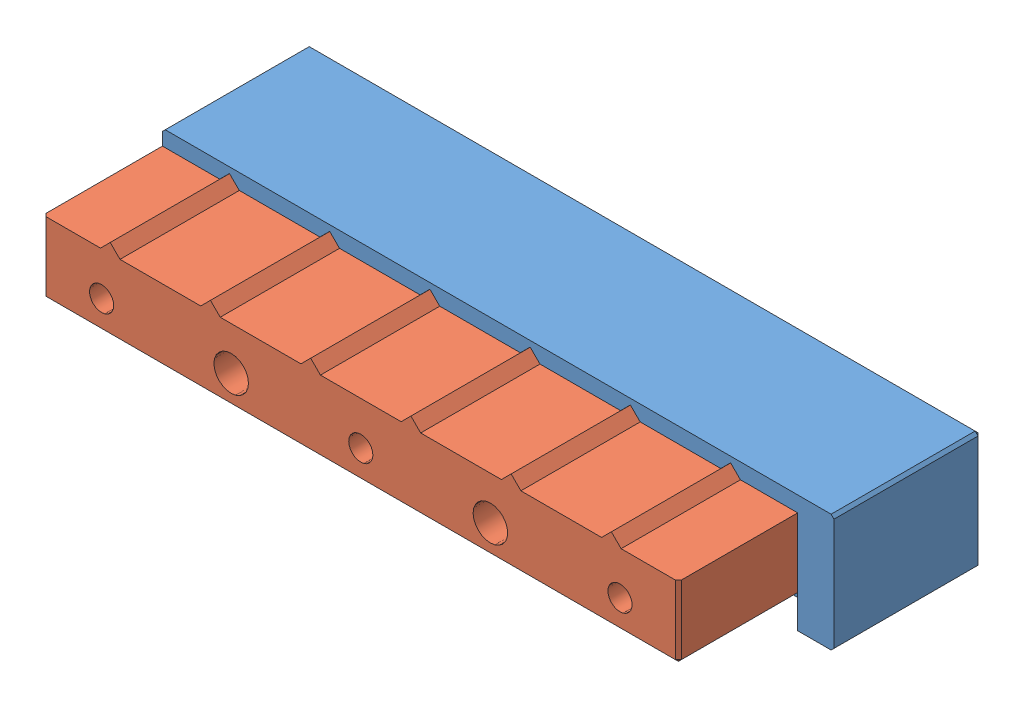
SolidWorks assembly Interferention check 28.06.19 , configuration По умолчанию. Lengths in mm.
Overall size (116.6 20.43 46.2).
2 component instances, 2 part files, 6 mates.
Components (placement in the parent):
- Upper Knife (28.07.19)-1: Upper Knife (28.07.19) [По умолчанию] at origin size (116.6 20.43 25.5)
- Lower Knife (28.07.19)-1: Lower Knife (28.07.19) [По умолчанию] at (0 5.24 20.7) size (110.28 14.17 25.5)
Mates (geometry in assembly coordinates):
- Концентричный1: concentric aligned: cylinder of Upper Knife (28.07.19)-1 through (32.65 10.23 -5) axis (0 0 1) radius 3; cylinder of Lower Knife (28.07.19)-1 through (32.65 10.23 20.7) axis (0 0 1) radius 3
- Концентричный2: concentric aligned: cylinder of Upper Knife (28.07.19)-1 through (77.65 10.23 -5) axis (0 0 1) radius 3; cylinder of Lower Knife (28.07.19)-1 through (77.65 10.23 20.7) axis (0 0 1) radius 3
- Концентричный3: concentric aligned: circle of Upper Knife (28.07.19)-1; cylinder of Lower Knife (28.07.19)-1 through (10.15 10.23 20.7) axis (0 0 1) radius 2.1
- Концентричный4: concentric aligned: cylinder of Upper Knife (28.07.19)-1 through (55.15 10.23 -5) axis (0 0 1) radius 2.1; cylinder of Lower Knife (28.07.19)-1 through (55.15 10.23 20.7) axis (0 0 1) radius 2.1
- Концентричный5: concentric aligned: cylinder of Upper Knife (28.07.19)-1 through (100.15 10.23 -5) axis (0 0 1) radius 2.1; cylinder of Lower Knife (28.07.19)-1 through (100.15 10.23 20.7) axis (0 0 1) radius 2.1
- Расстояние1: distance = 0.2 mm anti-aligned: plane of Upper Knife (28.07.19)-1 through (0 0 -5) normal (0 0 1); plane of Lower Knife (28.07.19)-1 through (0 5.24 -4.8) normal (0 0 -1)
